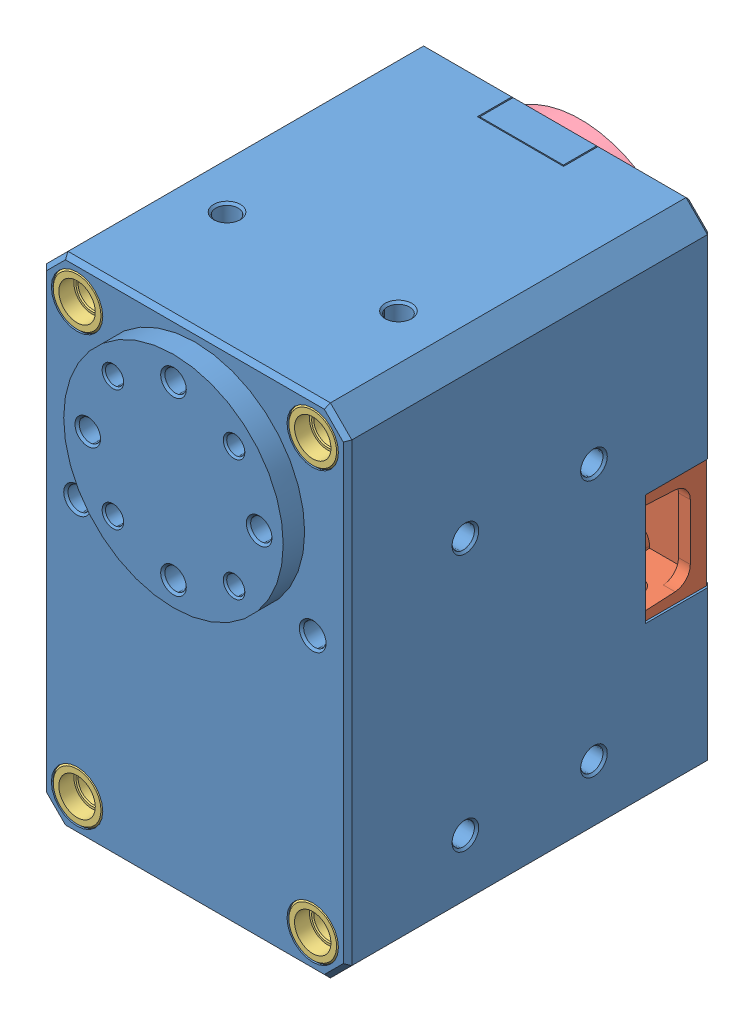
SolidWorks assembly XL-430, configuration Défaut. Lengths in mm.
Overall size (28.5 46.5 38).
13 component instances, 6 part files, 0 mates.
Components (placement in the parent):
- DC11_A01_DUMMY-1: DC11_A01_DUMMY [Défaut] at origin size (28.5 46.5 36)
- DC11_A01_CASE_CVR_DUMMY-1: DC11_A01_CASE_CVR_DUMMY [Défaut] at origin size (28.3 17.72 8.3)
- DC12_A01_SPACER_RING-1: DC12_A01_SPACER_RING [Défaut] at (-11 8 14.2) x (-1 0 0) z (0 1 0) size (4.75 2.8 4.75)
- DC12_A01_SPACER_RING-2: DC12_A01_SPACER_RING [Défaut] at (11 8 14.2) x (-1 0 0) z (0 1 0) size (4.75 2.8 4.75)
- DC12_A01_SPACER_RING-3: DC12_A01_SPACER_RING [Défaut] at (-11 -32 14.2) x (-1 0 0) z (0 1 0) size (4.75 2.8 4.75)
- DC12_A01_SPACER_RING-4: DC12_A01_SPACER_RING [Défaut] at (11 -32 14.2) x (-1 0 0) z (0 1 0) size (4.75 2.8 4.75)
- DC12_A01_SPACER_RING-5: DC12_A01_SPACER_RING [Défaut] at (11 -32 -14.2) x (1 0 0) z (0 1 0) size (4.75 2.8 4.75)
- DC12_A01_SPACER_RING-6: DC12_A01_SPACER_RING [Défaut] at (-11 -32 -14.2) x (1 0 0) z (0 1 0) size (4.75 2.8 4.75)
- DC12_A01_SPACER_RING-7: DC12_A01_SPACER_RING [Défaut] at (11 8 -14.2) x (1 0 0) z (0 1 0) size (4.75 2.8 4.75)
- DC12_A01_SPACER_RING-8: DC12_A01_SPACER_RING [Défaut] at (-11 8 -14.2) x (1 0 0) z (0 1 0) size (4.75 2.8 4.75)
- DC11_A01_IDLER_DUMMY-1: DC11_A01_IDLER_DUMMY [Défaut] at (0 0 -19) x (1 0 0) z (0 1 0) size (20.5 3.5 20.5)
- DC11_A01_IDLER_CAP_DUMMY-1: DC11_A01_IDLER_CAP_DUMMY [Défaut] at (0 0 -18.8) x (1 0 0) z (0 -1 0) size (12.1 4 9.81)
- PHS_M3X6-1: PHS_M3X6 [Défaut] at (0 0 -16.6) x (1 0 0) z (0 1 0) size (5.5 8 5.5)
